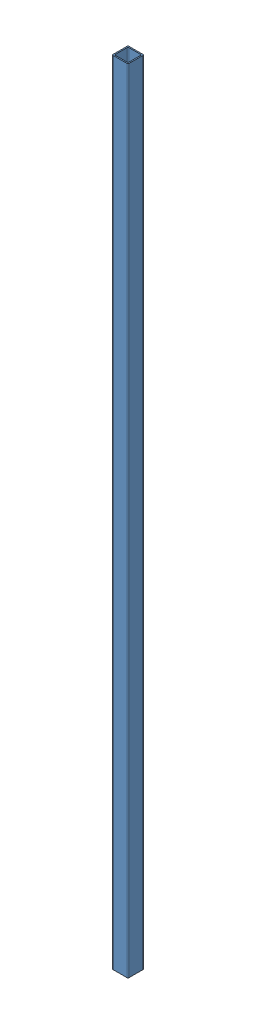
SolidWorks assembly Spar, configuration Default. Lengths in mm.
Overall size (367 1185.5 320).
23 component instances, 17 part files, 65 mates.
Components (placement in the parent):
- Tail Boom-1: Tail Boom [Default] at (20.2266 -517.2222 1.0272) size (20 1000 20) (hidden)
- Tail holder 1-1: Tail holder 1 [Default] at (31.2437 406.7778 -2.2179) x (1 0 0) z (0 -1 0) size (40 30 124) (hidden)
- tail holder 2-2: tail holder 2 [Default] at (21.0079 496.8403 300.9572) x (0 1 0) z (-1 0 0) size (10 323.08 10) (hidden)
- Tail Boom-2: Tail Boom [Default] at (-93.7734 -517.2222 1.0272) x (-1 0 0) z (0 0 -1) size (20 1000 20)
- Tail holder 1-3: Tail holder 1 [Default] at (-104.7904 406.7778 4.2723) x (-1 0 0) z (0 -1 0) size (40 30 124) (hidden)
- Vertical Stabilizer mk1-1: Vertical Stabilizer mk1 [Default] at (20.2266 346.1726 11.0272) x (-1 0 0) z (0 0 1) size (32.74 289.69 300.05) (hidden)
- tail holder 2-3: tail holder 2 [Default] at (-90.2109 492.4966 300.9572) x (1 0 0) z (0 1 0) size (10 323.08 10) (hidden)
- Vertical Stabilizer mk1-2: Vertical Stabilizer mk1 [Default] at (-93.7734 346.1726 11.0272) x (-1 0 0) z (0 0 1) size (32.74 289.69 300.05) (hidden)
- Horisontal stabiliser 11-1: Horisontal stabiliser 11 [Default] at (-336.7734 468.2778 304.1044) x (0 1 0) z (1 0 0) size (201.07 42.21 600) (hidden)
- top tail holder-1: top tail holder [Default] at (-94.9301 489.7185 257.1044) x (0 -1 0) z (-1 0 0) size (36 23 14) (hidden)
- top tail holder-3: top tail holder [Default] at (19.0699 489.7185 257.1044) x (0 -1 0) z (-1 0 0) size (36 23 14) (hidden)
- Horizontal stabilizer bar-1: Horizontal stabilizer bar [Default] at (-336.7734 503.5632 301.2248) x (0 0 -1) z (1 0 0) size (10 10 600) (hidden)
- Tail motor mount A mk1-1: Tail motor mount A mk1 [Default] at (-97.9309 255.7778 2.925) x (1 0 0) z (0 -1 0) size (55 30 50) (hidden)
- Tail motor mount A mk1-2: Tail motor mount A mk1 [Default] at (24.3842 255.7778 -0.8707) x (-1 0 0) z (0 -1 0) size (55 30 50) (hidden)
- Rear motor crossbar-1: Rear motor crossbar [Default] at (-83.7734 228.9438 2.5044) x (0 1 0) z (1 0 0) size (20 20 94) (hidden)
- Tail motor mount B mk1-1: Tail motor mount B mk1 [Default] at (-38.3549 230.7778 31.0272) x (-1 0 0) z (0 -1 0) size (24 47 40) (hidden)
- Servo mk1-1: Servo mk1 [Default] at (-101.0589 247.0979 -13.9728) x (0.971449 -0.237248 0) z (0.237248 0.971449 0) size (33.6 12.5 34.08) (hidden)
- Flap mk1-1: Flap mk1 [Default] at (-35.9741 313.2778 -18.4266) x (0.996557 0 -0.082916) z (0 -1 0) size (2 40 165) (hidden)
- Servo arm mk1-1: Servo arm mk1 [Default] at (-114.6733 232.8778 17.976) x (-0.995872 0 0.090763) z (0 -1 0) size (10.8 29.4 3.1) (hidden)
- Servo hook mk1-1: Servo hook mk1 [Default] at (-40.7562 235.7778 -42.4932) x (-0.996557 0 0.082916) z (0.082916 0 0.996557) size (6 10 10) (hidden)
- Servo wire-1: Servo wire [Default] at (-102.5419 227.3778 -25.7684) x (-0.039777 0 0.999209) z (0 1 0) size (2 59.28 13) (hidden)
- Tail motor-1: Tail motor [Default] at (-36.7734 230.7778 31.0272) x (-0.55385 -0.832617 0) z (0 0 -1) size (27.5 27.5 31.35) (hidden)
- tail prop-1: tail prop [Default] at (-36.7734 230.7778 54.3772) x (0.926424 -0.376482 0) z (-0.376482 -0.926424 0) size (111.23 11.43 97.73) (hidden)
Mates (geometry in assembly coordinates):
- Distance4: distance = 94 mm anti-aligned: plane of Tail Boom-1 through (10.2266 482.7778 10.0272) normal (-1 0 0); plane of Tail Boom-2 through (-83.7734 482.7778 -7.9728) normal (1 0 0)
- Coincident27: coincident aligned: plane of Tail Boom-1 through (11.2266 482.7778 -8.9728) normal (0 0 -1); plane of Tail Boom-2 through (-84.7734 482.7778 -8.9728) normal (0 0 -1)
- Coincident59: coincident anti-aligned: plane of Tail Boom-2 through (-84.7734 482.7778 -8.9728) normal (0 0 -1); plane of Tail holder 1-3 through (-104.7904 381.7778 -8.9728) normal (0 0 1)
- Coincident60: coincident anti-aligned: plane of Tail Boom-2 through (-103.7734 482.7778 -7.9728) normal (-1 0 0); plane of Tail holder 1-3 through (-103.7734 381.7778 4.2723) normal (1 0 0)
- Parallel1: parallel anti-aligned: plane of Tail Boom-2 through (-83.7734 482.7778 -7.9728) normal (1 0 0); plane of Tail holder 1-3 through (-83.7734 381.7778 4.2723) normal (-1 0 0)
- Coincident63: coincident anti-aligned: plane of Tail Boom-2 through (-84.7734 482.7778 -7.9728) normal (0 1 0); plane of Tail holder 1-3 through (-104.7904 482.7778 4.2723) normal (0 -1 0)
- Coincident64: coincident anti-aligned: plane of Tail Boom-1 through (11.2266 482.7778 10.0272) normal (0 1 0); plane of Tail holder 1-1 through (31.2437 482.7778 -2.2179) normal (0 -1 0)
- Coincident65: coincident anti-aligned: plane of Tail Boom-1 through (10.2266 482.7778 10.0272) normal (-1 0 0); plane of Tail holder 1-1 through (10.2266 381.7778 -2.2179) normal (1 0 0)
- Coincident66: coincident anti-aligned: plane of Tail Boom-1 through (11.2266 482.7778 11.0272) normal (0 0 1); plane of Tail holder 1-1 through (31.2437 381.7778 11.0272) normal (0 0 -1)
- Coincident67: coincident anti-aligned: plane of Tail holder 1-1 through (31.2437 498.2778 110.0272) normal (0 -1 0); plane of tail holder 2-2 through (25.2266 498.2778 -9.0428) normal (0 1 0)
- Coincident68: coincident aligned: plane of Tail holder 1-1 through (31.2437 381.7778 -13.9728) normal (0 0 -1); plane of tail holder 2-2 through (16.2266 489.2778 -13.9728) normal (0 0 -1)
- Coincident69: coincident anti-aligned: plane of Tail holder 1-1 through (15.2266 406.7778 110.0272) normal (1 0 0); plane of tail holder 2-2 through (15.2266 488.2778 -9.0428) normal (-1 0 0)
- Coincident71: coincident aligned: plane of Tail holder 1-3 through (-104.7904 381.7778 -13.9728) normal (0 0 -1); plane of tail holder 2-3 through (-97.7734 497.2778 -13.9728) normal (0 0 -1)
- Coincident72: coincident anti-aligned: plane of Tail holder 1-3 through (-88.7734 406.7778 -107.9728) normal (-1 0 0); plane of tail holder 2-3 through (-88.7734 488.2778 -9.0428) normal (1 0 0)
- Coincident73: coincident anti-aligned: plane of Horisontal stabiliser 11-1 through (-336.7734 486.2778 267.1044) normal (0 1 0); plane of top tail holder-3 through (27.2266 486.2778 297.1044) normal (0 -1 0)
- Coincident74: coincident anti-aligned: plane of Horisontal stabiliser 11-1 through (27.2266 468.2778 267.1044) normal (-1 0 0); plane of top tail holder-3 through (27.2266 500.2778 297.1044) normal (1 0 0)
- Coincident75: coincident anti-aligned: plane of Horisontal stabiliser 11-1 through (-336.7734 468.2778 311.1044) normal (0 0 -1); plane of top tail holder-3 through (19.0699 489.7185 311.1044) normal (0 0 1)
- Coincident76: coincident anti-aligned: plane of Horisontal stabiliser 11-1 through (-100.7734 468.2778 267.1044) normal (1 0 0); plane of top tail holder-1 through (-100.7734 500.2778 297.1044) normal (-1 0 0)
- Coincident77: coincident anti-aligned: plane of Horisontal stabiliser 11-1 through (-336.7734 486.2778 267.1044) normal (0 1 0); plane of top tail holder-1 through (-86.7734 486.2778 297.1044) normal (0 -1 0)
- Coincident78: coincident anti-aligned: plane of Horisontal stabiliser 11-1 through (-336.7734 468.2778 311.1044) normal (0 0 -1); plane of top tail holder-1 through (-94.9301 489.7185 311.1044) normal (0 0 1)
- Coincident81: coincident anti-aligned: plane of Horisontal stabiliser 11-1 through (-390.7734 500.2778 304.1044) normal (0 1 0); plane of Horizontal stabilizer bar-1 through (263.2266 500.2778 309.1044) normal (0 -1 0)
- Coincident83: coincident anti-aligned: plane of Horisontal stabiliser 11-1 through (-390.7734 468.2778 309.1044) normal (0 0 -1); plane of Horizontal stabilizer bar-1 through (263.2266 510.2778 309.1044) normal (0 0 1)
- Coincident84: coincident aligned: plane of Horisontal stabiliser 11-1 through (263.2266 468.2778 304.1044) normal (1 0 0); plane of Horizontal stabilizer bar-1 through (263.2266 503.5632 301.2248) normal (1 0 0)
- Coincident86: coincident anti-aligned: plane of tail holder 2-3 through (-88.7734 488.2778 -9.0428) normal (1 0 0); plane of Vertical Stabilizer mk1-2 through (-88.7734 346.1726 321.0272) normal (-1 0 0)
- Coincident87: coincident anti-aligned: plane of tail holder 2-3 through (-98.7734 488.2778 -9.0428) normal (0 -1 0); plane of Vertical Stabilizer mk1-2 through (-93.7734 488.2778 321.0272) normal (0 1 0)
- Coincident89: coincident anti-aligned: plane of tail holder 2-2 through (25.2266 488.2778 -9.0428) normal (0 -1 0); plane of Vertical stabiliser 11-1 through (20.2266 488.2778 321.0272) normal (0 1 0)
- Coincident90: coincident anti-aligned: plane of tail holder 2-2 through (15.2266 488.2778 -9.0428) normal (-1 0 0); plane of Vertical stabiliser 11-1 through (15.2266 346.1726 321.0272) normal (1 0 0)
- Coincident91: coincident anti-aligned: plane of tail holder 2-2 through (25.2266 488.2778 -9.0428) normal (1 0 0); plane of top tail holder-3 through (25.2266 489.7185 257.1044) normal (-1 0 0)
- Coincident92: coincident anti-aligned: plane of tail holder 2-2 through (25.2266 488.2778 -9.0428) normal (0 -1 0); plane of top tail holder-3 through (19.0699 488.2778 257.1044) normal (0 1 0)
- Distance5: distance = 311.0772 mm: line of top tail holder-1 through (-87.7734 500.2778 297.1044) axis (-1 0 0); plane of tail holder 2-3 through (-97.7734 497.2778 -13.9728) normal (0 0 -1)
- Coincident93: coincident anti-aligned: plane of Tail Boom-1 through (11.2266 482.7778 11.0272) normal (0 0 1); plane of Vertical stabiliser 11-1 through (20.2266 346.1726 11.0272) normal (0 0 -1)
- Coincident94: coincident anti-aligned: plane of Tail Boom-2 through (-84.7734 482.7778 11.0272) normal (0 0 1); plane of Vertical Stabilizer mk1-2 through (-93.7734 346.1726 11.0272) normal (0 0 -1)
- Coincident95: coincident anti-aligned: plane of Tail Boom-2 through (-84.7734 482.7778 -8.9728) normal (0 0 -1); plane of Tail motor mount A mk1-1 through (-103.7734 205.7778 -8.9728) normal (0 0 1)
- Coincident96: coincident anti-aligned: plane of Tail Boom-2 through (-103.7734 482.7778 -7.9728) normal (-1 0 0); plane of Tail motor mount A mk1-1 through (-103.7734 205.7778 11.0272) normal (1 0 0)
- Distance6: distance = 126 mm anti-aligned: plane of Tail holder 1-3 through (-104.7904 381.7778 4.2723) normal (0 -1 0); plane of Tail motor mount A mk1-1 through (-97.9309 255.7778 2.925) normal (0 1 0)
- Coincident98: coincident anti-aligned: plane of Tail Boom-1 through (10.2266 482.7778 10.0272) normal (-1 0 0); plane of Tail motor mount A mk1-2 through (10.2266 205.7778 -8.9728) normal (1 0 0)
- Coincident99: coincident anti-aligned: plane of Tail Boom-1 through (11.2266 482.7778 -8.9728) normal (0 0 -1); plane of Tail motor mount A mk1-2 through (30.2266 205.7778 -8.9728) normal (0 0 1)
- Distance7: distance = 126 mm anti-aligned: plane of Tail holder 1-1 through (31.2437 381.7778 -2.2179) normal (0 -1 0); plane of Tail motor mount A mk1-2 through (24.3842 255.7778 -0.8707) normal (0 1 0)
- Coincident101: coincident anti-aligned: plane of Tail motor mount A mk1-1 through (-103.7734 205.7778 -8.9728) normal (0 0 1); plane of Rear motor crossbar-1 through (10.2266 220.7778 -8.9728) normal (0 0 -1)
- Coincident102: coincident anti-aligned: plane of Tail motor mount A mk1-1 through (-48.7734 240.7778 11.0272) normal (0 -1 0); plane of Rear motor crossbar-1 through (10.2266 240.7778 11.0272) normal (0 1 0)
- Coincident103: coincident anti-aligned: plane of Tail Boom-1 through (10.2266 482.7778 10.0272) normal (-1 0 0); plane of Rear motor crossbar-1 through (10.2266 228.9438 2.5044) normal (1 0 0)
- Coincident104: coincident anti-aligned: plane of Rear motor crossbar-1 through (10.2266 220.7778 -8.9728) normal (0 0 -1); plane of Tail motor mount B mk1-1 through (-9.7734 230.7778 -8.9728) normal (0 0 1)
- Coincident105: coincident anti-aligned: plane of Rear motor crossbar-1 through (10.2266 240.7778 11.0272) normal (0 1 0); plane of Tail motor mount B mk1-1 through (-9.7734 240.7778 31.0272) normal (0 -1 0)
- Distance8: distance = 15 mm anti-aligned: plane of Tail motor mount B mk1-1 through (-48.7734 230.7778 31.0272) normal (-1 0 0); plane of Tail motor mount A mk1-1 through (-63.7734 255.7778 2.925) normal (1 0 0)
- Width2: width anti-aligned: plane of Tail motor mount B mk1-1 through (-38.3549 215.7778 11.0272) normal (0 -1 0); plane of Flap mk1-1 through (-38.3549 245.7778 11.0272) normal (0 1 0); plane of Tail motor mount B mk1-1 through (-35.9741 313.2778 -18.4266) normal (0 1 0); plane of Flap mk1-1 through (-35.9741 148.2778 -18.4266) normal (0 -1 0)
- Coincident109: coincident anti-aligned: line of Tail motor mount B mk1-1 through (-36.7734 215.7778 -15.9728) axis (0 1 0); line of Flap mk1-1 through (-36.7734 313.2778 -15.9728) axis (0 -1 0)
- LimitAngle1: limit planar angle = 1.487785 rad anti-aligned: plane of Flap mk1-1 through (-37.7699 148.2778 -15.8899) normal (-0.996557 0 0.082916); plane of Tail motor mount B mk1-1 through (-9.7734 215.7778 -13.9728) normal (0 0 -1)
- Coincident111: coincident anti-aligned: plane of Tail motor mount A mk1-1 through (-108.7734 205.7778 -13.9728) normal (0 0 -1); plane of Servo mk1-1 through (-101.0589 247.0979 -13.9728) normal (0 0 1)
- Width3: width anti-aligned: plane of Servo mk1-1 through (-105.2734 260.1778 -26.4728) normal (-1 0 0); plane of Tail motor mount A mk1-1 through (-82.2734 260.1778 -26.4728) normal (1 0 0); plane of Servo mk1-1 through (-78.7734 205.7778 16.0272) normal (1 0 0); plane of Tail motor mount A mk1-1 through (-108.7734 205.7778 16.0272) normal (-1 0 0)
- Distance9: distance = 24 mm aligned: plane of Servo mk1-1 through (-101.0589 229.7778 -13.9728) normal (0 -1 0); plane of Tail motor mount A mk1-1 through (-97.9309 205.7778 2.925) normal (0 -1 0)
- Coincident114: coincident anti-aligned: cylinder of Servo mk1-1 through (-99.0234 229.7778 -20.2228) axis (0 1 0) radius 2.4; circle of Servo arm mk1-1
- Coincident115: coincident aligned: plane of Servo mk1-1 through (-101.0589 229.7778 -13.9728) normal (0 -1 0); plane of Servo arm mk1-1 through (-114.6733 229.7778 17.976) normal (0 -1 0)
- Coincident117: coincident anti-aligned: plane of Flap mk1-1 through (-37.7699 148.2778 -15.8899) normal (-0.996557 0 0.082916); plane of Servo hook mk1-1 through (-40.1231 225.7778 -44.1722) normal (0.996557 0 -0.082916)
- Width5: width aligned: plane of Servo hook mk1-1 through (-40.7562 225.7778 -42.4932) normal (0 -1 0); plane of Flap mk1-1 through (-40.7562 235.7778 -42.4932) normal (0 1 0); plane of Servo hook mk1-1 through (-35.9741 148.2778 -18.4266) normal (0 -1 0); plane of Flap mk1-1 through (-35.9741 313.2778 -18.4266) normal (0 1 0)
- Distance12: distance = 11.62 mm aligned: plane of Servo hook mk1-1 through (-40.1231 225.7778 -44.1722) normal (-0.082916 0 -0.996557); plane of Flap mk1-1 through (-41.0866 148.2778 -55.7522) normal (-0.082916 0 -0.996557)
- LimitAngle3: limit planar angle = 1.661685 rad anti-aligned: plane of Servo arm mk1-1 through (-120.1754 229.7778 -42.3945) normal (-0.090763 0 -0.995872); plane of Tail motor mount A mk1-1 through (-108.7734 205.7778 16.0272) normal (-1 0 0)
- Concentric2: concentric aligned: cylinder of Servo arm mk1-1 through (-100.9294 229.7778 -41.1362) axis (0 1 0) radius 1; cylinder of Servo wire-1 through (-100.9294 219.8778 -41.1362) axis (0 1 0) radius 1
- Concentric3: concentric anti-aligned: cylinder of Servo hook mk1-1 through (-43.6947 244.7778 -38.8577) axis (0 -1 0) radius 1; cylinder of Servo wire-1 through (-43.6947 168.0978 -38.8577) axis (0 1 0) radius 1
- Coincident122: coincident aligned: plane of Servo arm mk1-1 through (-114.6733 232.8778 17.976) normal (0 1 0); plane of Servo wire-1 through (-100.9294 232.8778 -41.1362) normal (0 1 0)
- Coincident123: coincident anti-aligned: plane of Tail holder 1-3 through (-104.7904 488.2778 -107.9728) normal (0 1 0); plane of tail holder 2-3 through (-98.7734 488.2778 -9.0428) normal (0 -1 0)
- Coincident125: coincident anti-aligned: plane of Tail motor mount A mk1-2 through (-24.7734 240.7778 -8.9728) normal (0 -1 0); plane of Rear motor crossbar-1 through (10.2266 240.7778 11.0272) normal (0 1 0)
- Concentric13: concentric aligned: cylinder of Tail motor mount B mk1-1 through (-36.7734 230.7778 26.0272) axis (0 0 1) radius 11; cylinder of Tail motor-1 through (-36.7734 230.7778 62.3772) axis (0 0 1) radius 13.75
- Coincident126: coincident anti-aligned: plane of Tail motor mount B mk1-1 through (-38.3549 230.7778 31.0272) normal (0 0 1); plane of Tail motor-1 through (-36.7734 230.7778 31.0272) normal (0 0 -1)
- Concentric14: concentric anti-aligned: cylinder of Tail motor-1 through (-36.7734 230.7778 62.3772) axis (0 0 1) radius 2.5; cylinder of tail prop-1 through (-36.7734 230.7778 62.3772) axis (0 0 -1) radius 2.5
- Coincident127: coincident aligned: plane of Tail motor-1 through (-38.158 228.6963 62.3772) normal (0 0 1); plane of tail prop-1 through (-36.7734 230.7778 62.3772) normal (0 0 1)
